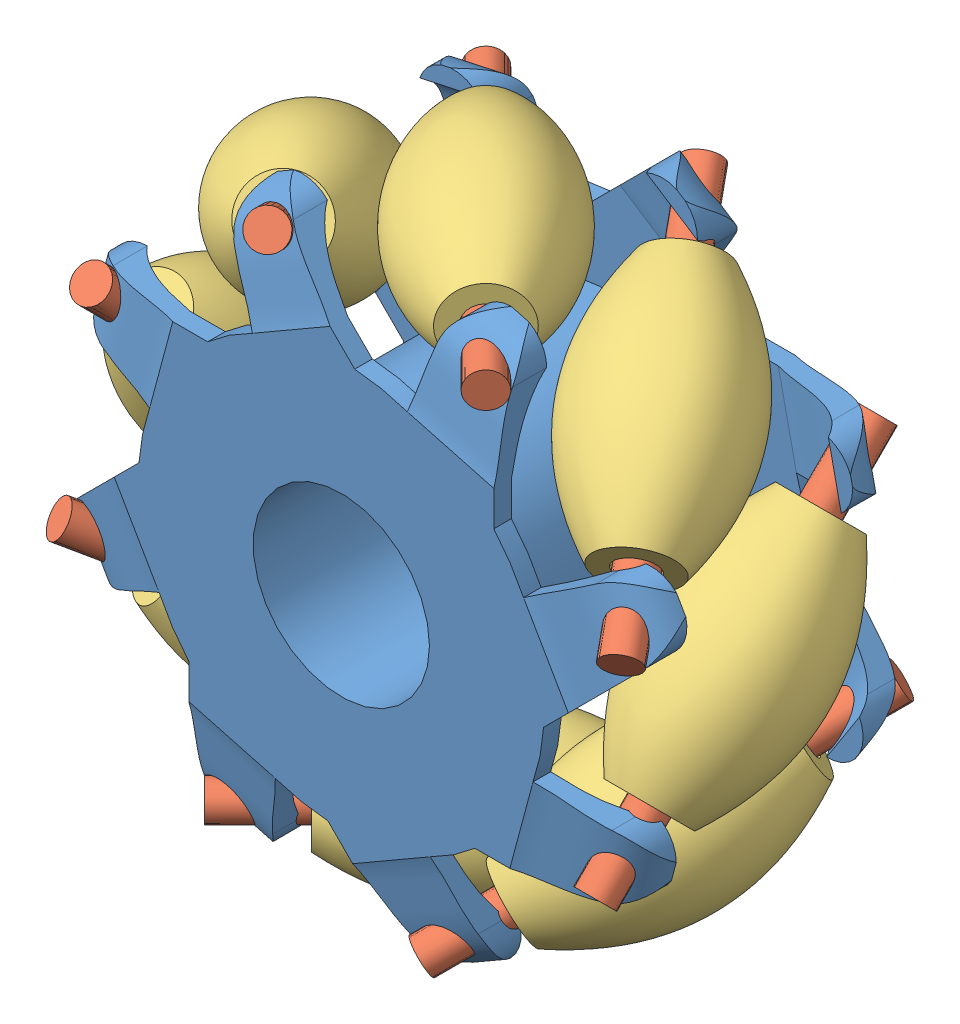
SolidWorks assembly wheel, configuration Default. Lengths in mm.
Overall size (76.83 81.27 37.08).
17 component instances, 3 part files, 32 mates.
Components (placement in the parent):
- wheel_rim-1: wheel_rim [Default] at (23.0349 31.7496 68.9855) size (66.41 66.41 33.64)
- wheel_rod-1: wheel_rod [Default] at (31.9487 62.9022 38.8541) x (0.856785 0.166642 -0.488006) z (0.5 -0.5 0.707107) size (4 4 45)
- wheel_rod-2: wheel_rod [Default] at (-7.9946 40.7866 39.0282) x (0.617473 -0.778325 0.11374) z (0.5 0.5 0.707107) size (4 4 45)
- wheel_rod-3: wheel_rod [Default] at (54.2645 22.9128 38.7451) x (-0.442639 -0.554242 -0.704902) z (-0.5 -0.5 0.707107) size (4 4 45)
- wheel_rod-4: wheel_rod [Default] at (7.6312 60.0809 39.1756) x (0.377915 0.845198 -0.377915) z (0.707107 0 0.707107) size (4 4 45)
- wheel_rod-5: wheel_rod [Default] at (13.7494 0.9687 39.3796) x (0.865366 0.320317 0.385408) z (-0.5 0.5 0.707107) size (4 4 45)
- wheel_rod-6: wheel_rod [Default] at (51.3661 47.6388 38.6901) x (-0.591968 -0.569901 -0.569901) z (0 -0.707107 0.707107) size (4 4 45)
- wheel_rod-7: wheel_rod [Default] at (38.8818 3.4184 38.7323) x (0.666027 -0.33588 0.666027) z (-0.707107 0 0.707107) size (4 4 45)
- wheel_rod-8: wheel_rod [Default] at (-5.2964 16.3913 39.2209) x (0.983109 -0.129414 0.129414) z (0 0.707107 0.707107) size (4 4 45)
- wheel_roller-2: wheel_roller [Default] at (51.3661 31.6936 54.6353) x (0.946359 -0.228478 -0.228479) z (0.323117 0.669177 0.669177) size (17.4 27.5 17.4)
- wheel_roller-3: wheel_roller [Default] at (-5.2964 31.983 54.8126) x (1 0 0) z (0 -0.707107 0.707107) size (17.4 27.5 17.4)
- wheel_roller-4: wheel_roller [Default] at (2.8244 11.8936 54.8299) x (0.455111 0.846365 -0.276658) z (0.7368 -0.183483 0.650738) size (17.4 27.5 17.4)
- wheel_roller-5: wheel_roller [Default] at (23.435 60.0809 54.9794) x (0.5 -0.707107 -0.5) z (-0.5 -0.707107 0.5) size (17.4 27.5 17.4)
- wheel_roller-6: wheel_roller [Default] at (22.8658 3.4184 54.7483) x (0.5 -0.707107 0.5) z (0.5 0.707107 0.5) size (17.4 27.5 17.4)
- wheel_roller-7: wheel_roller [Default] at (3.1804 51.9616 54.832) x (0.833333 -0.5 -0.235702) z (-0.235702 -0.707107 0.666667) size (17.4 27.5 17.4)
- wheel_roller-8: wheel_roller [Default] at (42.9395 11.5878 54.7611) x (0.833333 -0.5 0.235702) z (0.235702 0.707107 0.666667) size (17.4 27.5 17.4)
- wheel_roller-9: wheel_roller [Default] at (43.3237 51.5272 54.9408) x (0.63932 0.76388 0.088077) z (-0.584183 0.408029 0.7016) size (17.4 27.5 17.4)
Mates (geometry in assembly coordinates):
- Coincident1: coincident aligned: axis of wheel_rim-1 through (53.5669 41.284 69.4268) axis (-0.5 0.5 -0.707107); axis of wheel_rod-1 through (54.4487 40.4022 70.6739) axis (-0.5 0.5 -0.707107)
- Lock2: lock: unknown of wheel_rim-1; unknown of wheel_rod-1
- Coincident2: coincident aligned: axis of wheel_rim-1 through (38.5931 60.0809 70.1375) axis (-0.707107 0 -0.707107); axis of wheel_rod-4 through (39.451 60.0809 70.9954) axis (-0.707107 0 -0.707107)
- Lock3: lock: unknown of wheel_rim-1; unknown of wheel_rod-4
- Coincident3: coincident aligned: axis of wheel_rim-1 through (12.8898 61.6711 68.5633) axis (-0.5 -0.5 -0.707107); axis of wheel_rod-2 through (14.5053 63.2866 70.848) axis (-0.5 -0.5 -0.707107)
- Lock4: lock: unknown of wheel_rim-1; unknown of wheel_rod-2
- Coincident4: coincident aligned: axis of wheel_rim-1 through (-5.2964 45.0825 67.9121) axis (0 -0.707107 -0.707107); axis of wheel_rod-8 through (-5.2964 48.2111 71.0407) axis (0 -0.707107 -0.707107)
- Lock5: lock: unknown of wheel_rim-1; unknown of wheel_rod-8
- Coincident5: coincident aligned: axis of wheel_rim-1 through (-6.8866 21.6046 68.5633) axis (0.5 -0.5 -0.707107); axis of wheel_rod-5 through (-8.7506 23.4686 71.1994) axis (0.5 -0.5 -0.707107)
- Lock6: lock: unknown of wheel_rim-1; unknown of wheel_rod-5
- Coincident6: coincident aligned: axis of wheel_rim-1 through (9.702 3.4184 67.9121) axis (0.707107 0 -0.707107); axis of wheel_rod-7 through (7.062 3.4184 70.5521) axis (0.707107 0 -0.707107)
- Lock7: lock: unknown of wheel_rim-1; unknown of wheel_rod-7
- Coincident7: coincident aligned: axis of wheel_rim-1 through (32.5692 1.2176 69.4268) axis (0.5 0.5 -0.707107); axis of wheel_rod-3 through (31.7645 0.4128 70.5649) axis (0.5 0.5 -0.707107)
- Lock8: lock: unknown of wheel_rim-1; unknown of wheel_rod-3
- Coincident8: coincident aligned: axis of wheel_rim-1 through (51.3661 16.1914 70.1375) axis (0 0.707107 -0.707107); axis of wheel_rod-6 through (51.3661 15.819 70.5099) axis (0 0.707107 -0.707107)
- Lock9: lock: unknown of wheel_rim-1; unknown of wheel_rod-6
- Coincident10: coincident aligned: axis of wheel_rod-6 through (51.3661 15.819 70.5099) axis (0 0.707107 -0.707107); axis of wheel_roller-2 through (51.3661 26.4748 59.8541) axis (0 0.707107 -0.707107)
- Distance1: distance = 8.7 mm aligned: plane of wheel_roller-2 through (53.4481 21.4682 63.8554) normal (0 -0.707107 0.707107); plane of wheel_rod-6 through (51.3661 15.819 70.5099) normal (0 -0.707107 0.707107)
- Coincident11: coincident aligned: axis of wheel_rod-1 through (54.4487 40.4022 70.6739) axis (-0.5 0.5 -0.707107); axis of wheel_roller-9 through (47.0139 47.837 60.1595) axis (-0.5 0.5 -0.707107)
- Distance2: distance = 8.5 mm aligned: plane of wheel_rod-1 through (54.4487 40.4022 70.6739) normal (0.5 -0.5 0.707107); plane of wheel_roller-9 through (51.6052 46.3328 64.8573) normal (0.5 -0.5 0.707107)
- Coincident12: coincident anti-aligned: axis of wheel_rod-4 through (39.451 60.0809 70.9954) axis (-0.707107 0 -0.707107); axis of wheel_roller-5 through (18.2162 60.0809 49.7606) axis (0.707107 0 0.707107)
- Distance3: distance = 8.9 mm aligned: plane of wheel_rod-4 through (39.451 60.0809 70.9954) normal (0.707107 0 0.707107); plane of wheel_roller-5 through (34.2577 58.5253 63.6021) normal (0.707107 0 0.707107)
- Coincident13: coincident anti-aligned: axis of wheel_rod-2 through (14.5053 63.2866 70.848) axis (-0.5 -0.5 -0.707107); axis of wheel_roller-7 through (-0.5099 48.2714 49.6132) axis (0.5 0.5 0.707107)
- Distance4: distance = 8.9 mm aligned: plane of wheel_rod-2 through (14.5053 63.2866 70.848) normal (0.5 0.5 0.707107); plane of wheel_roller-7 through (11.8887 57.7366 64.0362) normal (0.5 0.5 0.707107)
- Coincident15: coincident anti-aligned: axis of wheel_rod-8 through (-5.2964 48.2111 71.0407) axis (0 -0.707107 -0.707107); axis of wheel_roller-3 through (-5.2964 26.7642 49.5938) axis (0 0.707107 0.707107)
- Distance5: distance = 9.2 mm aligned: plane of wheel_roller-3 through (-3.0964 41.7057 64.5353) normal (0 0.707107 0.707107); plane of wheel_rod-8 through (-5.2964 48.2111 71.0407) normal (0 0.707107 0.707107)
- Coincident17: coincident anti-aligned: axis of wheel_rod-5 through (-8.7506 23.4686 71.1994) axis (0.5 -0.5 -0.707107); axis of wheel_roller-4 through (6.5146 8.2034 49.6111) axis (-0.5 0.5 0.707107)
- Distance6: distance = 9.4 mm aligned: plane of wheel_roller-4 through (-3.0493 20.6307 63.9439) normal (-0.5 0.5 0.707107); plane of wheel_rod-5 through (-8.7506 23.4686 71.1994) normal (-0.5 0.5 0.707107)
- Coincident18: coincident aligned: axis of wheel_rod-7 through (7.062 3.4184 70.5521) axis (0.707107 0 -0.707107); axis of wheel_roller-6 through (17.6471 3.4184 59.967) axis (0.707107 0 -0.707107)
- Distance7: distance = 8.6 mm aligned: plane of wheel_rod-7 through (7.062 3.4184 70.5521) normal (-0.707107 0 0.707107); plane of wheel_roller-6 through (14.2431 1.8628 65.571) normal (-0.707107 0 0.707107)
- Coincident20: coincident aligned: axis of wheel_rod-3 through (31.7645 0.4128 70.5649) axis (0.5 0.5 -0.707107); axis of wheel_roller-8 through (39.2493 7.8976 59.9799) axis (0.5 0.5 -0.707107)
- Distance8: distance = 8.6 mm aligned: plane of wheel_rod-3 through (31.7645 0.4128 70.5649) normal (-0.5 -0.5 0.707107); plane of wheel_roller-8 through (37.8978 3.6128 65.0024) normal (-0.5 -0.5 0.707107)
